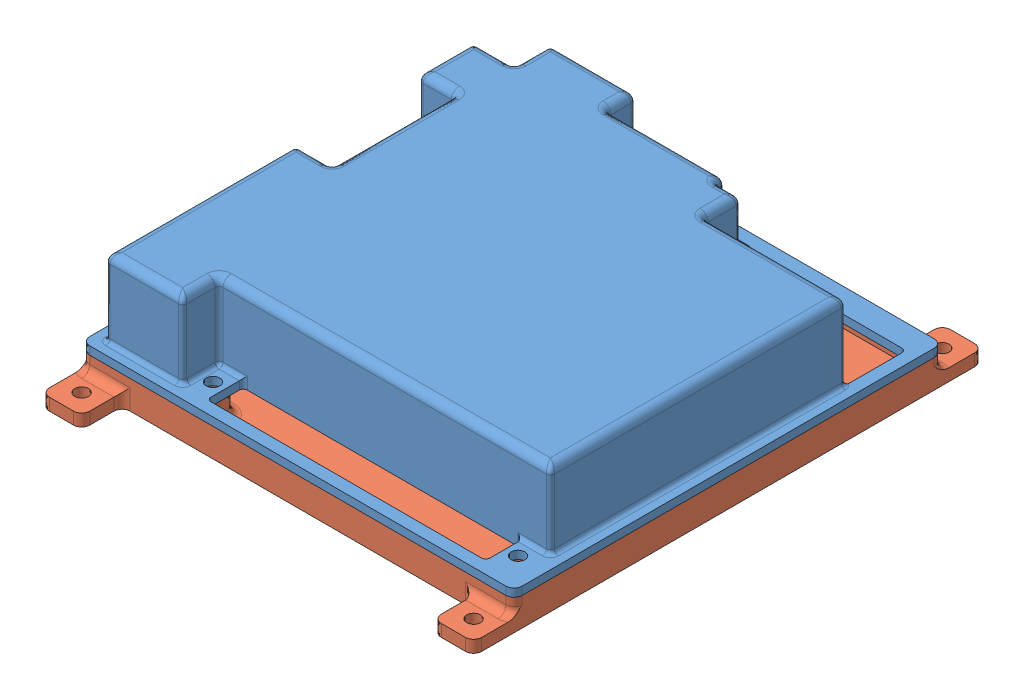
SolidWorks assembly Assem1, configuration Default. Lengths in mm.
Overall size (107 28.13 126).
2 component instances, 2 part files, 2 mates.
Components (placement in the parent):
- MCU top-1: MCU top [Default] at (-38.523 83.2029 78.7896) x (1 0 0) z (0 1 0) size (107 106 21.13)
- base-1: base [Default] at (-38.523 56.2029 78.7896) x (0 0 -1) z (0 1 0) size (126 107 7)
Mates (geometry in assembly coordinates):
- Concentric1: concentric anti-aligned: cylinder of MCU top-1 through (7.977 63.2029 123.7896) axis (0 1 0) radius 1.7; cylinder of base-1 through (7.977 63.2029 123.7896) axis (0 -1 0) radius 2
- Coincident1: coincident anti-aligned: plane of MCU top-1 through (-38.523 63.2029 78.7896) normal (0 -1 0); plane of base-1 through (-38.523 63.2029 78.7896) normal (0 1 0)
